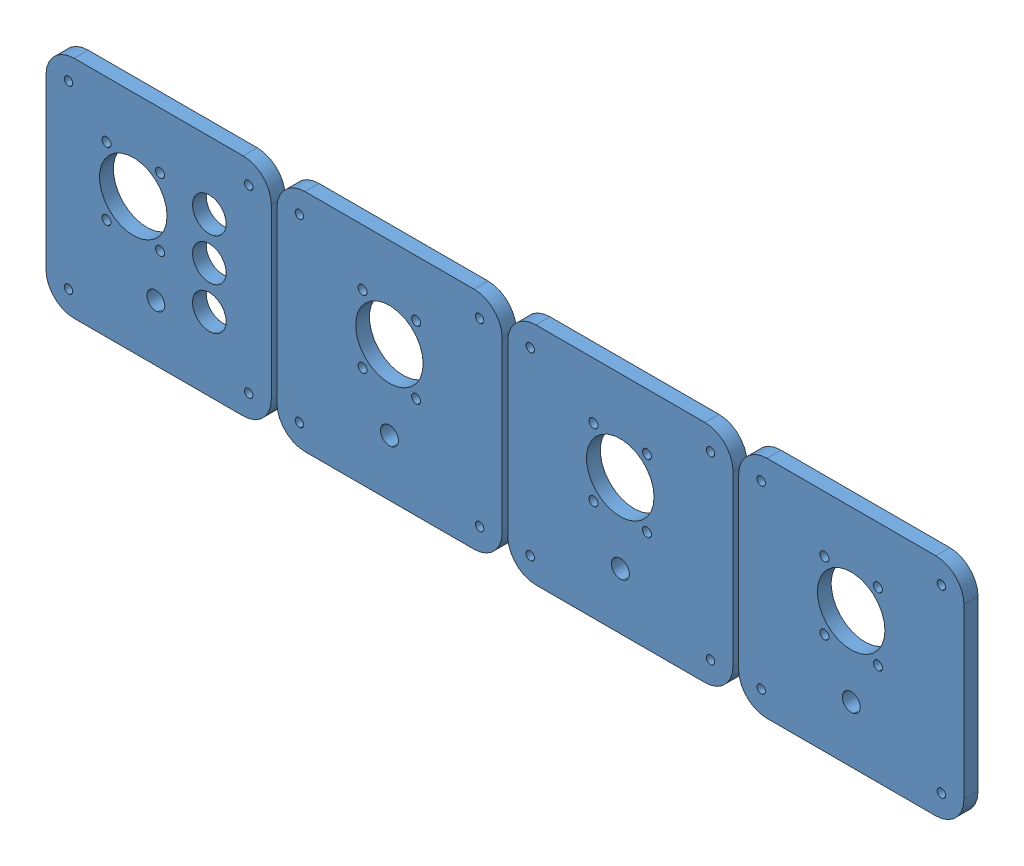
SolidWorks assembly plaque, configuration Défaut. Lengths in mm.
Overall size (326 80 19).
4 component instances, 1 part files, 9 mates.
Components (placement in the parent):
- plaque-1: plaque [banane] at origin size (80 80 19)
- plaque-2: plaque [xlr] at (82 0 0) size (80 80 19)
- plaque-3: plaque [xlr] at (164 0 0) size (80 80 19)
- plaque-4: plaque [xlr] at (246 0 0) size (80 80 19)
Mates (geometry in assembly coordinates):
- Coïncidente1: coincident aligned: plane of plaque-1 through (-40 40 5) normal (0 1 0); plane of plaque-2 through (42 40 5) normal (0 1 0)
- Coïncidente2: coincident aligned: plane of plaque-1 through (0 0 5) normal (0 0 1); plane of plaque-2 through (82 0 5) normal (0 0 1)
- Distance1: distance anti-aligned: plane of plaque-1 through (40 40 5) normal (1 0 0); plane of plaque-2 through (42 40 5) normal (-1 0 0)
- Coïncidente3: coincident aligned: plane of plaque-2 through (42 40 5) normal (0 1 0); plane of plaque-3 through (124 40 5) normal (0 1 0)
- Coïncidente4: coincident aligned: plane of plaque-2 through (82 0 5) normal (0 0 1); plane of plaque-3 through (164 0 5) normal (0 0 1)
- Distance2: distance anti-aligned: plane of plaque-2 through (122 40 5) normal (1 0 0); plane of plaque-3 through (124 40 5) normal (-1 0 0)
- Coïncidente5: coincident aligned: plane of plaque-3 through (124 40 5) normal (0 1 0); plane of plaque-4 through (206 40 5) normal (0 1 0)
- Coïncidente6: coincident aligned: plane of plaque-3 through (164 0 5) normal (0 0 1); plane of plaque-4 through (246 0 5) normal (0 0 1)
- Distance3: distance anti-aligned: plane of plaque-3 through (204 40 5) normal (1 0 0); plane of plaque-4 through (206 40 5) normal (-1 0 0)
